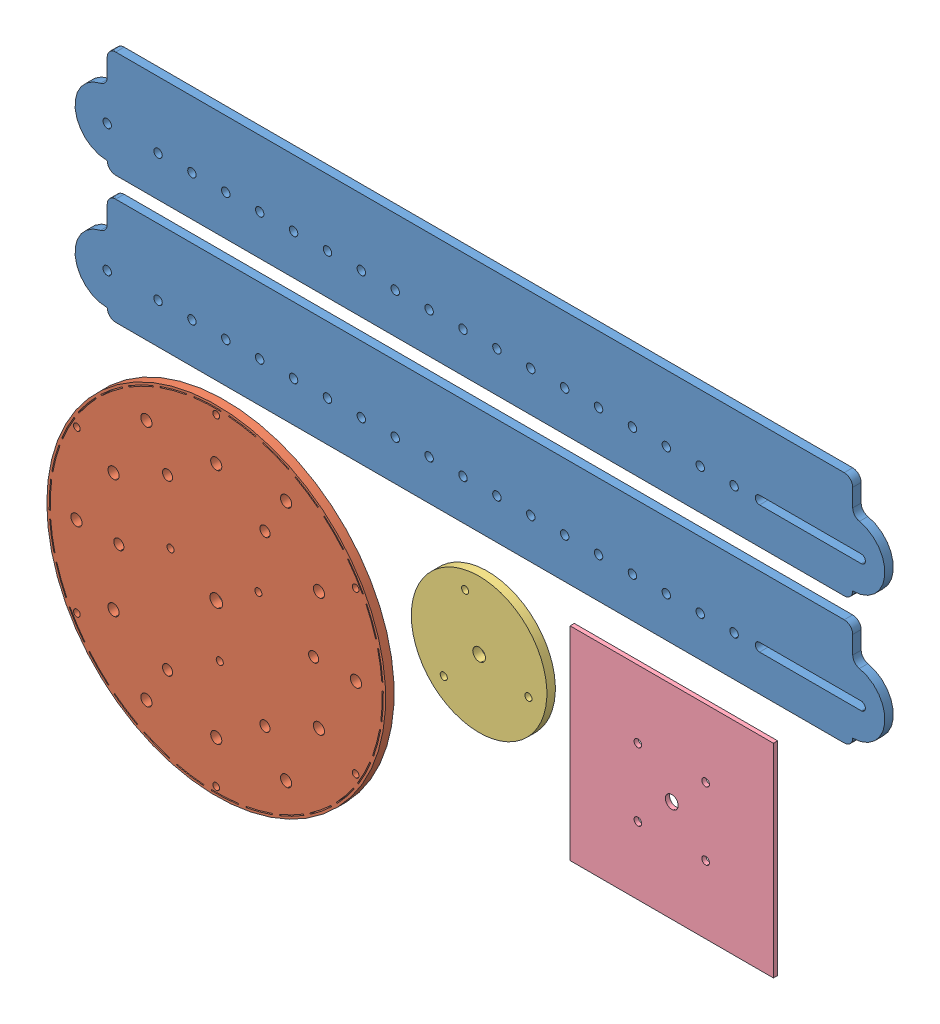
SolidWorks assembly LaserCuttingAppt, configuration Default. Lengths in mm.
Overall size (628.2 445.41 7.94).
5 component instances, 4 part files, 0 mates.
Components (placement in the parent):
- Side Piece-1: Side Piece [Default] at (-120.453 429.1235 476.869) size (607.06 80.01 6.35)
- Side Piece-2: Side Piece [Default] at (-120.453 524.6293 476.869) size (607.06 80.01 6.35)
- Baskethubpt1wire-1: Baskethubpt1wire [Default] at (-38.7273 255.7485 473.694) x (0 1 0) z (1 0 0) size (254 6.35 254)
- baskethubpt2motor-1: baskethubpt2motor [Default] at (158.3023 319.3318 473.694) size (101.6 101.6 6.35)
- DumpingPlate-1: DumpingPlate [Default] at (304.3083 297.3524 480.044) x (0 1 0) z (1 0 0) size (152.4 3.17 152.4)
